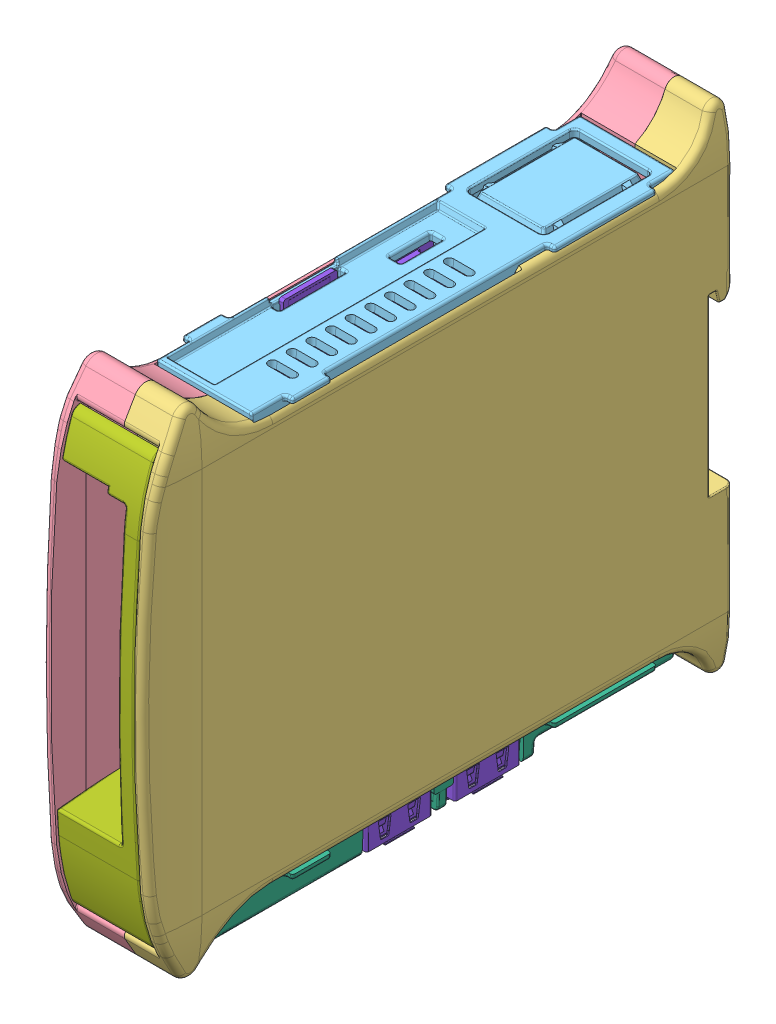
SolidWorks assembly raspberry_assembly, configuration Default. Lengths in mm.
Overall size (23.89 101.81 119.94).
8 component instances, 8 part files, 3 mates.
Components (placement in the parent):
- 65615_01-1: 65615_01 [Default] at origin size (4.3 11.01 4.3)
- 65615_02-1: 65615_02 [Default] at origin size (14 35.8 5)
- 65615_03-1: 65615_03 [Default] at origin size (10.97 101.43 119.94)
- 65615_04-1: 65615_04 [Default] at origin size (12.93 101.42 119.94)
- 65615_05-1: 65615_05 [Default] at origin size (22.71 7.85 88.5)
- 65615_06-1: 65615_06 [Default] at origin size (22.5 12.84 97.29)
- 65615_07-1: 65615_07 [Default] at origin size (17.99 87.87 23.64)
- RaspberryPi3-1: RaspberryPi3 [Default] at (-7.87 -8.742 70.2107) x (0 -1 0) z (1 0 0) size (89.64 57.31 18.59)
Mates (geometry in assembly coordinates):
- Coincident5: coincident anti-aligned: plane of 65615_05-1 through (-4.8 39.7 67.7) normal (0 -1 0); plane of RaspberryPi3-1 through (-8.63 39.7 42.79) normal (0 1 0)
- Distance1: distance = 2.8 mm anti-aligned: plane of RaspberryPi3-1 through (-8.2 -45.2242 39.8) normal (-1 0 0); plane of 65615_04-1 through (-11 0 53.7) normal (1 0 0)
- Distance2: distance = 1.4 mm anti-aligned: plane of 65615_04-1 through (0 50 97.2) normal (0 0 -1); plane of RaspberryPi3-1 through (-8.63 36.71 95.8) normal (0 0 1)
